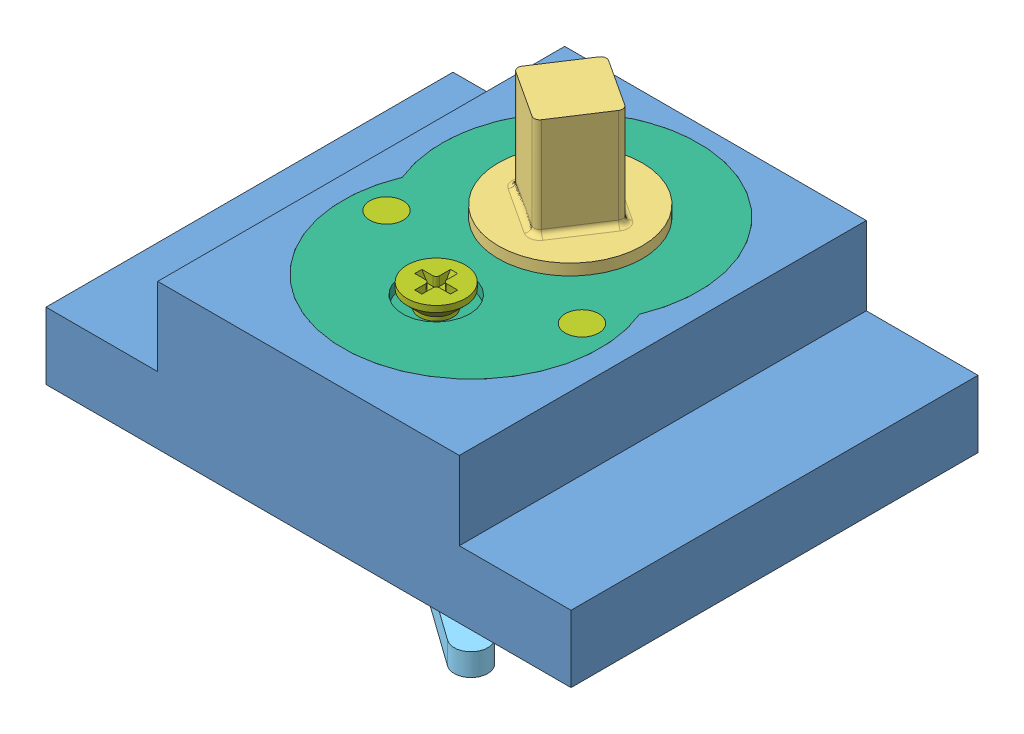
SolidWorks assembly 装配体棘轮2, configuration 默认. Lengths in mm.
Overall size (53.55 26 48).
9 component instances, 7 part files, 19 mates.
Components (placement in the parent):
- 棘轮壳-1: 棘轮壳 [默认] at origin size (47 13 36)
- 棘轮顶片右-1: 棘轮顶片右 [默认] at (2.7 11 10.7323) x (-0.777454 0 0.62894) z (0 -1 0) size (11.42 7.53 11)
- 棘轮轮齿-1: 棘轮轮齿 [默认] at (0 14 -7.7) x (-0.837169 0 -0.546944) z (-0.546944 0 0.837169) size (17.03 26 17.02)
- 棘轮顶片-2: 棘轮顶片 [默认] at (-2.7 3 10.7323) x (0.641267 0 0.767318) z (0 1 0) size (11.42 7.53 11)
- 棘轮凸轮-1: 棘轮凸轮 [默认] at (0 3 4.3) x (0.998151 0 0.060788) z (0 1 0) size (33.86 25.66 8)
- 棘轮盖板-1: 棘轮盖板 [默认] at (0 11 -7.7) x (1 0 0) z (0 1 0) size (23 31.84 2)
- cross recessed countersunk head screws gb2-6: cross recessed countersunk head screws gb2 [GB_CROSS_SCREWS_TYPE10 M3X14-12.35-H1-N] at (-8.75 -1 0) x (0 1 0) z (0.24814 0 0.968724) size (14 5.2 5.2)
- cross recessed countersunk head screws gb2-7: cross recessed countersunk head screws gb2 [GB_CROSS_SCREWS_TYPE10 M3X14-12.35-H1-N] at (8.75 -1 0) x (0 1 0) z (0 0 1) size (14 5.2 5.2)
- cross recessed countersunk head screws gb2-8: cross recessed countersunk head screws gb2 [GB_CROSS_SCREWS_TYPE10 M3X8-6.35-H1-N] at (0 14 4.3) x (0 -1 0) z (0 0 1) size (8 5.2 5.2)
Mates (geometry in assembly coordinates):
- 重合2: coincident anti-aligned: plane of 棘轮壳-1 through (0 3 0) normal (0 1 0); plane of 棘轮轮齿-1 through (-5.3914 3 -11.2223) normal (0 -1 0)
- 同心2: concentric aligned: cylinder of 棘轮壳-1 through (0 3 -7.7) axis (0 -1 0) radius 6.75; cylinder of 棘轮轮齿-1 through (0 -3 -7.7) axis (0 -1 0) radius 6.44
- 同心3: concentric anti-aligned: cylinder of 棘轮壳-1 through (2.7 3 10.7323) axis (0 -1 0) radius 1.5; cylinder of 棘轮顶片右-1 through (2.7 3 10.7323) axis (0 1 0) radius 1.4
- 重合3: coincident anti-aligned: plane of 棘轮壳-1 through (0 3 0) normal (0 1 0); plane of 棘轮顶片右-1 through (4.9372 3 9.8633) normal (0 -1 0)
- 同心4: concentric aligned: cylinder of 棘轮壳-1 through (-2.7 3 10.7323) axis (0 -1 0) radius 1.5; cylinder of 棘轮顶片-2 through (-2.7 11 10.7323) axis (0 -1 0) radius 1.4
- 重合4: coincident anti-aligned: plane of 棘轮壳-1 through (0 3 0) normal (0 1 0); plane of 棘轮顶片-2 through (-4.7271 3 9.4474) normal (0 -1 0)
- 同心5: concentric anti-aligned: cylinder of 棘轮壳-1 through (0 3 4.3) axis (0 -1 0) radius 1.5; cylinder of 棘轮凸轮-1 through (0 0 4.3) axis (0 1 0) radius 1.5
- 重合5: coincident anti-aligned: plane of 棘轮壳-1 through (0 3 0) normal (0 1 0); plane of 棘轮凸轮-1 through (0 3 4.3) normal (0 -1 0)
- 相切1: tangent anti-aligned: plane of 棘轮顶片-2 through (-1.3208 11 10.4919) normal (0.98515 0 -0.171695); cylinder of 棘轮凸轮-1 through (-0.7828 6 3.6777) axis (0 -1 0) radius 1.7
- 相切2: tangent anti-aligned: plane of 棘轮顶片右-1 through (1.3932 3 10.2299) normal (-0.933405 0 -0.358824); cylinder of 棘轮凸轮-1 through (-0.4691 6 3.927) axis (0 -1 0) radius 4
- 同心6: concentric aligned: cylinder of 棘轮轮齿-1 through (0 -3 -7.7) axis (0 -1 0) radius 6.44; cylinder of 棘轮盖板-1 through (0 13 -7.7) axis (0 -1 0) radius 6.44
- 同心7: concentric anti-aligned: cylinder of 棘轮壳-1 through (8.75 3 0) axis (0 -1 0) radius 1.25; cylinder of cross recessed countersunk head screws gb2-7 through (8.75 3.5158 0) axis (0 1 0) radius 1.5
- 重合8: coincident aligned: plane of 棘轮盖板-1 through (0 13 -7.7) normal (0 1 0); plane of cross recessed countersunk head screws gb2-7 through (7.25 13 0) normal (0 1 0)
- 同心8: concentric anti-aligned: cylinder of 棘轮壳-1 through (-8.75 3 0) axis (0 -1 0) radius 1.25; cylinder of cross recessed countersunk head screws gb2-6 through (-8.75 3.5158 0) axis (0 1 0) radius 1.5
- 重合9: coincident aligned: plane of 棘轮盖板-1 through (0 13 -7.7) normal (0 1 0); plane of cross recessed countersunk head screws gb2-6 through (-10.2031 13 0.3722) normal (0 1 0)
- 同心9: concentric aligned: cylinder of 棘轮盖板-1 through (0 13 4.3) axis (0 -1 0) radius 1.5; cylinder of cross recessed countersunk head screws gb2-8 through (0 9.4842 4.3) axis (0 -1 0) radius 1.5
- 重合10: coincident anti-aligned: plane of 棘轮凸轮-1 through (0 6 4.3) normal (0 1 0); plane of cross recessed countersunk head screws gb2-8 through (1.5 6 4.3) normal (0 -1 0)
- 同心10: concentric aligned: cylinder of 棘轮壳-1 through (0 11 1.1386) axis (0 1 0) radius 11.5; cylinder of 棘轮盖板-1 through (0 11 1.1386) axis (0 1 0) radius 11.5
- 重合11: coincident anti-aligned: plane of 棘轮壳-1 through (0 11 -3.2807) normal (0 1 0); plane of 棘轮盖板-1 through (0 11 -7.7) normal (0 -1 0)
